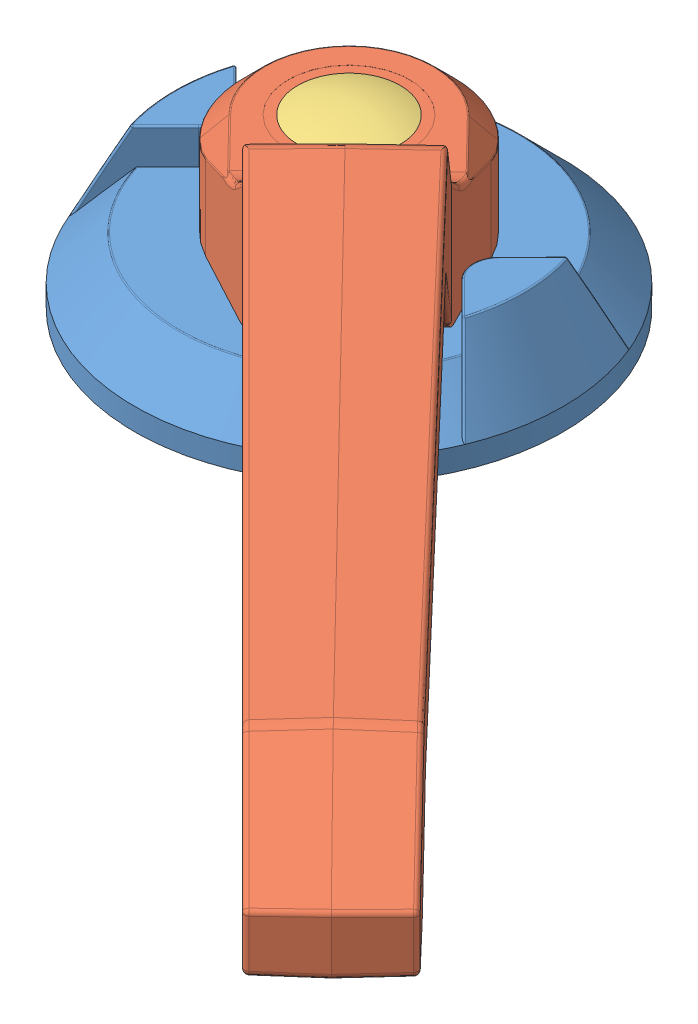
SolidWorks assembly Ручка DIDAK, configuration По умолчанию. Lengths in mm.
Overall size (169.1 55.2 171.71).
3 component instances, 3 part files, 5 mates.
Components (placement in the parent):
- Накладка Со Стопором 232-0410.03-1: Накладка Со Стопором 232-0410.03 [По умолчанию] at origin size (70 21.3 70)
- Ручка 176-1: Ручка 176 [По умолчанию] at (13.4157 30.7 13.7353) x (0.698733 0 0.715383) z (0 -1 0) size (191.5 34.6 51)
- Заглушка D14 (Черная)-1: Заглушка D14 (Черная) [По умолчанию] at (0 27.39 0) x (0.892078 0 -0.451881) z (0.451881 0 0.892078) size (16.7 8.3 16.7)
Mates (geometry in assembly coordinates):
- Концентричный1: concentric aligned: cylinder of Накладка Со Стопором 232-0410.03-1 through (0 3.8 0) axis (0 1 0) radius 12.6; cylinder of Ручка 176-1 through (0 3.8 0) axis (0 1 0) radius 12.35
- Совпадение1: coincident anti-aligned: plane of Накладка Со Стопором 232-0410.03-1 through (0 10.8 0) normal (0 1 0); plane of Ручка 176-1 through (0 10.8 0) normal (0 -1 0)
- Концентричный2: concentric aligned: cylinder of Ручка 176-1 through (0 19.59 0) axis (0 1 0) radius 7.5; cylinder of Заглушка D14 (Черная)-1 through (0 26.89 0) axis (0 1 0) radius 6.7
- Совпадение2: coincident anti-aligned: plane of Ручка 176-1 through (0 27.39 0) normal (0 1 0); plane of Заглушка D14 (Черная)-1 through (7.4489 27.39 -3.7732) normal (0 -1 0)
- Граничный угол1: limit planar angle = 1.570796 rad aligned: plane of Ручка 176-1 through (4.7774 50.5 22.1725) normal (-0.707107 0 0.707107); plane of Накладка Со Стопором 232-0410.03-1 through (-32.186 3.6 13.75) normal (0.707107 0 0.707107)
